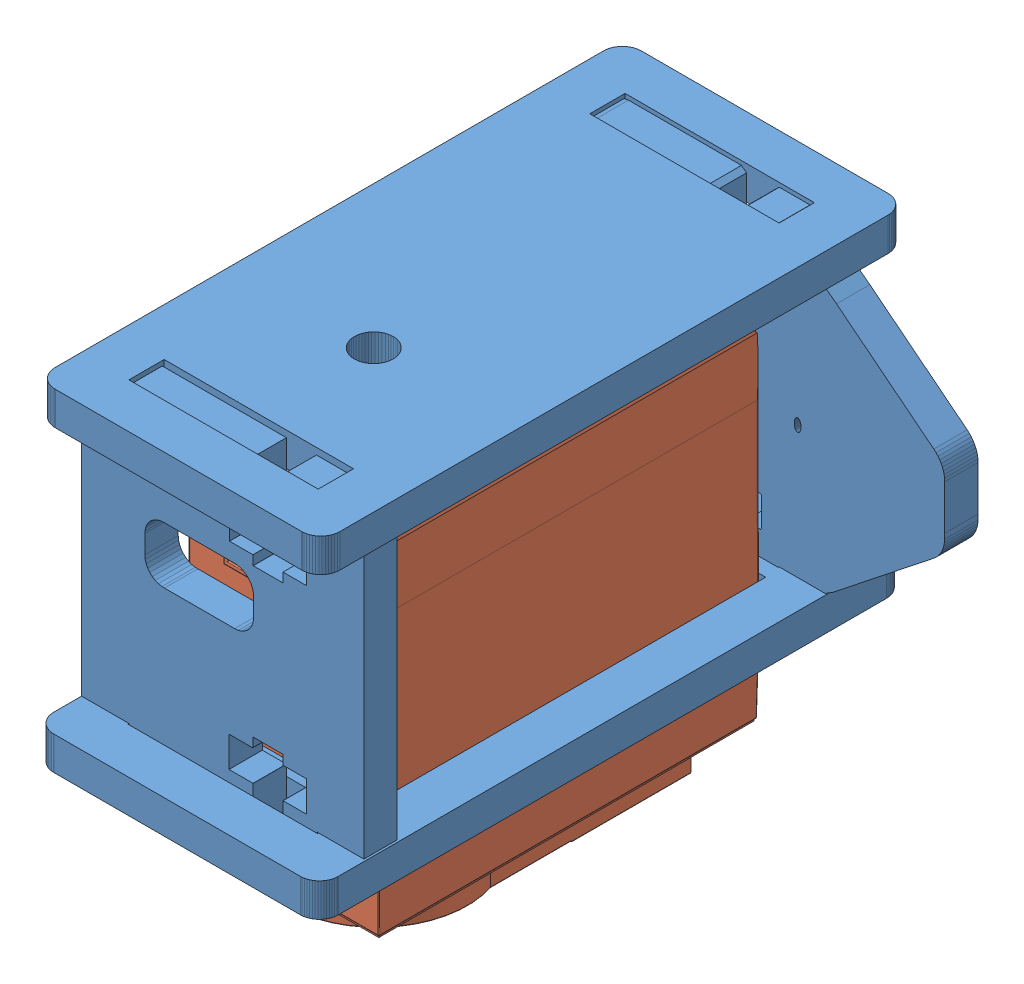
SolidWorks assembly left_shoulder_upper_arm_clamp, configuration Default. Lengths in mm.
Overall size (55.01 47.38 61.58).
4 component instances, 3 part files, 2 mates.
Components (placement in the parent):
- left_shoulder_upper_arm_clamp_100-1: left_shoulder_upper_arm_clamp_100 [Default] at (-13.0142 14.7955 26.1068) size (55.01 34.84 61.58)
- main_assembly-1: main_assembly [Default] at (-0.6006 73.2369 17.5681) x (0.999998 0.00176 0) z (0.00176 -0.999998 0) size (20 53 41.5)
  - main_body-1: main_body [Default] at (15.1003 34.2066 38.7045) size (20 53 41.5)
- hs-422_horn_2wings_sws-1: hs-422_horn_2wings_sws [Default] at (14.2349 31.9343 24.0581) x (-0.004258 0.999991 0) z (0.999991 0.004258 0) size (9.1 5 34)
Mates (geometry in assembly coordinates):
- Coincident2: coincident anti-aligned: line of left_shoulder_upper_arm_clamp_100-1 through (24.603 14.5767 72.8603) axis (0 0 -1); line of main_assembly-1/main_body-1 through (24.603 14.5767 32.0247) axis (0 0 1)
- Concentric1: concentric aligned: circle of left_shoulder_upper_arm_clamp_100-1; circle of hs-422_horn_2wings_sws-1
